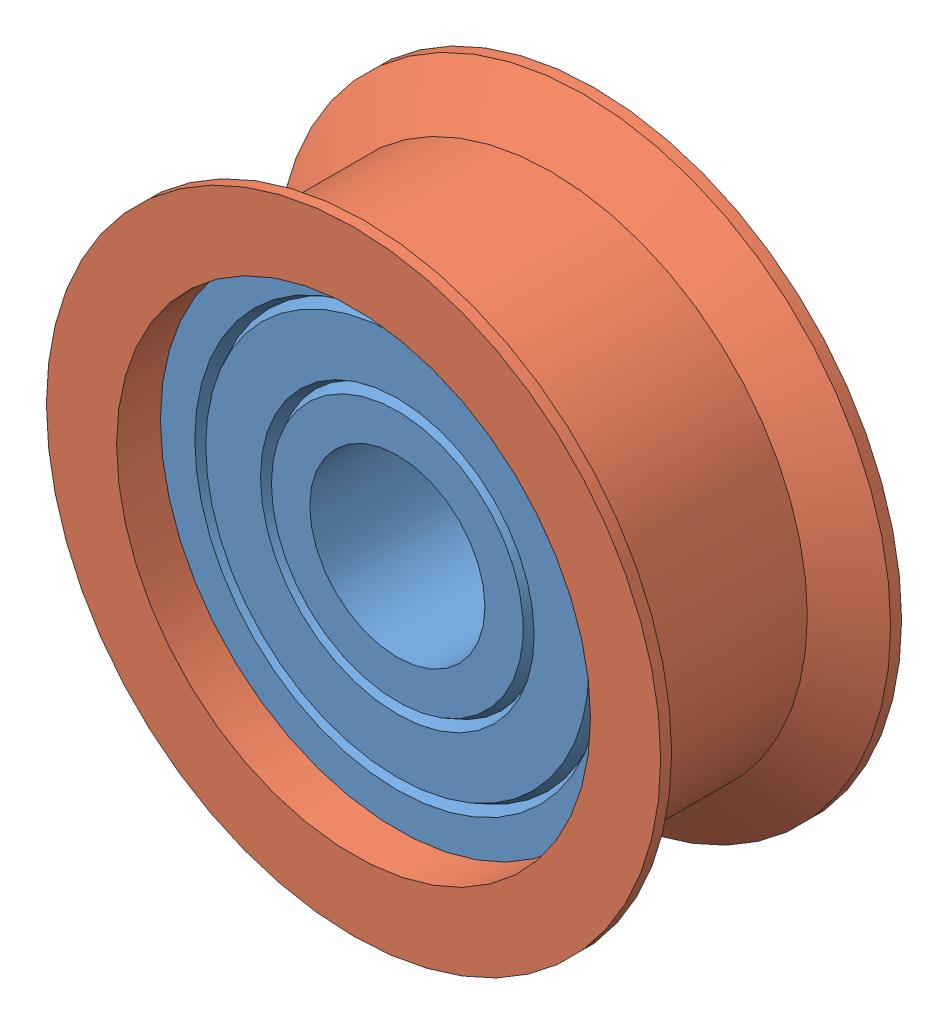
SolidWorks assembly skatepulley, configuration Default. Lengths in mm.
Overall size (28.05 28.05 11).
2 component instances, 2 part files, 2 mates.
Components (placement in the parent):
- SkateBearing-1: SkateBearing [Default] at (-6.2594 12.248 24.002) size (22 22 7)
- skatepulley-1: skatepulley [Default] at (-6.2594 12.248 24.002) x (0 0 -1) z (1 0 0) size (11 28.05 28.05)
Mates (geometry in assembly coordinates):
- Concentric1: concentric anti-aligned: cylinder of SkateBearing-1 through (-6.2594 12.248 24.002) axis (0 0 1) radius 11; cylinder of skatepulley-1 through (-6.2594 12.248 24.002) axis (0 0 -1) radius 11.22
- Coincident1: coincident anti-aligned: plane of SkateBearing-1 through (-17.2594 12.248 27.502) normal (0 0 1); plane of skatepulley-1 through (-6.2594 23.068 27.502) normal (0 0 -1)
